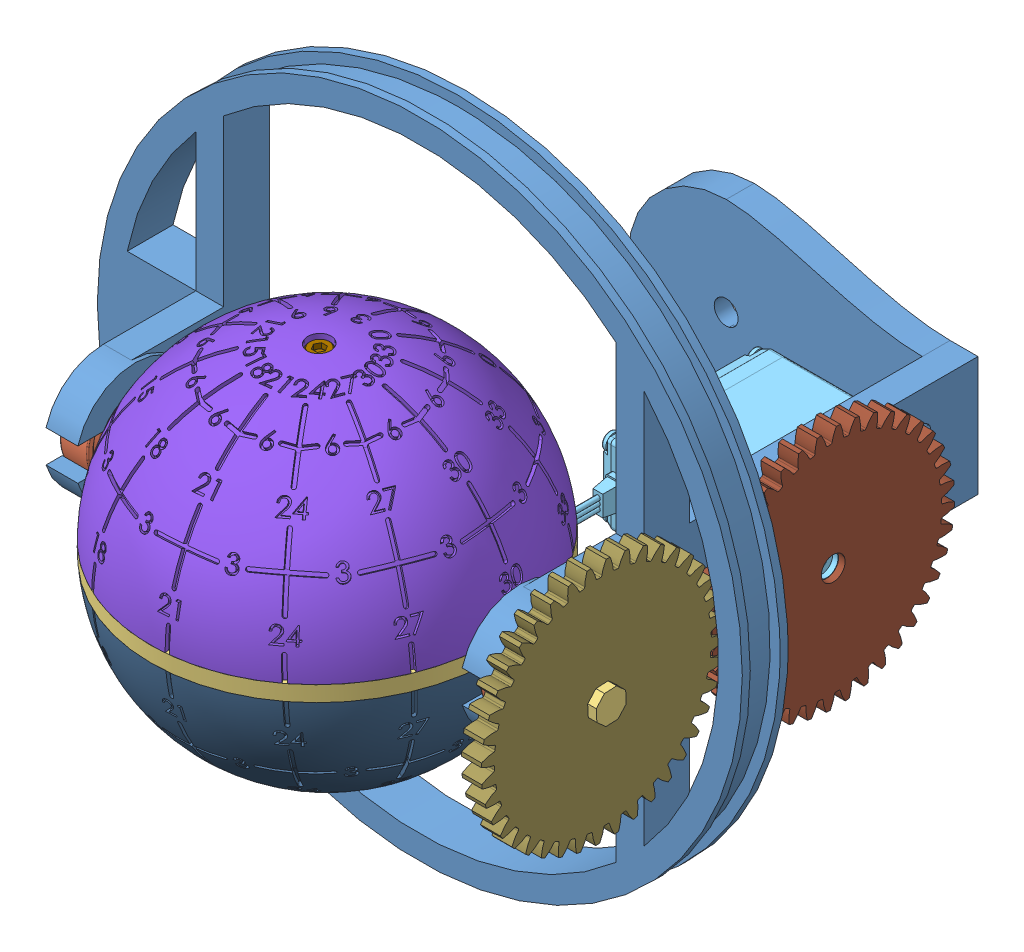
SolidWorks assembly Pitch2, configuration Default. Lengths in mm.
Overall size (162 162 168.07).
16 component instances, 12 part files, 15 mates.
Components (placement in the parent):
- PitchBracketV2-1: PitchBracketV2 [Default] at origin size (162 162 121.57)
- Ball Bearing 608ZZ-2: Ball Bearing 608ZZ [Défaut] at (-52.75 0 -1.875) x (0 0 -1) z (-1 0 0) size (22 22 7)
- Ball Bearing 608ZZ-3: Ball Bearing 608ZZ [Défaut] at (52.75 0 -1.875) x (0 0 -1) z (1 0 0) size (22 22 7)
- Yaw-1: Yaw [Default] at (-53.019 -60.801 -96.8449) x (1 0 0) z (0 -0.046911 0.998899) size (130.2 88.9 117.86)
  - BallPlate-1: BallPlate [Default] at (53.019 65.1893 92.0131) size (127.54 8 88.9)
  - SKF 625-1: SKF 625 [Default] at (53.019 62.6893 92.0131) x (0 1 0) z (-0.440998 0 0.897508) size (5 16 16)
  - Servo-1: Servo [noHorn] at (53.019 67.1893 71.9881) x (0 0 -1) z (1 0 0) size (19.8 47.23 67)
  - YawServoGear-1: YawServoGear [Default] at (42.719 84.6893 71.9881) x (-0.590306 0 0.80718) z (0 -1 0) size (24.43 24.43 4)
  - BallShaft_V2-1: BallShaft_V2 [Default] at (53.019 65.1893 92.0131) x (-0.986105 0 0.166123) z (-0.166123 0 -0.986105) size (24.43 75.9 24.43)
  - Ball_V9.1_Top-1: Ball_V9.1_Top [Default] at (53.019 65.1893 92.0131) x (-0.907868 0 -0.419257) z (0.419257 0 -0.907868) size (88.8 42.45 88.81)
  - socket head cap screw_am-1: socket head cap screw_am [B18.3.1M - 3 x 0.5 x 20 Hex SHCS -- 20SHX] at (53.019 108.6393 92.0131) x (0 -1 0) z (0 0 1) size (23 5.5 5.5)
  - Ball_V9.1_Bot-1: Ball_V9.1_Bot [Default] at (53.019 65.1893 92.0131) x (-0.907868 0 -0.419257) z (0.419257 0 -0.907868) size (88.8 87.56 88.81)
  - socket head cap screw_am-2: socket head cap screw_am [B18.3.1M - 3 x 0.5 x 20 Hex SHCS -- 20SHX] at (53.019 21.7393 92.0131) x (0 1 0) z (0.546944 0 -0.837169) size (23 5.5 5.5)
- Servo-1: Servo [Default] at (47.25 0 -70.05) x (0 1 0) z (0 0 -1) size (19.8 47.23 67)
- PitchServoGear-1: PitchServoGear [Default] at (69.15 0 -59.75) x (0 -0.80252 -0.596625) z (-1 0 0) size (60.99 60.99 5)
- PitchGear-1: PitchGear [Default] at (64.15 0 -1.875) x (0 0.061118 -0.998131) z (1 0 0) size (60.99 60.99 12.6)
Mates (geometry in assembly coordinates):
- Concentric2: concentric: circle of PitchBracketV2-1; circle of Ball Bearing 608ZZ-2
- Width2: width: plane of PitchBracketV2-1 through (-56.25 -15 -55.6183) normal (-1 0 0); plane of PitchBracketV2-1 through (-49.25 0 -152.5832) normal (1 0 0); plane of Ball Bearing 608ZZ-2 through (-49.25 0 -1.875) normal (1 0 0); plane of Ball Bearing 608ZZ-2 through (-56.25 0 -1.875) normal (-1 0 0)
- Concentric3: concentric: circle of Ball Bearing 608ZZ-3; circle of PitchBracketV2-1
- Width3: width: plane of PitchBracketV2-1 through (49.25 15 0) normal (-1 0 0); plane of PitchBracketV2-1 through (56.25 15 0) normal (1 0 0); plane of Ball Bearing 608ZZ-3 through (56.25 0 -1.875) normal (1 0 0); plane of Ball Bearing 608ZZ-3 through (49.25 0 -1.875) normal (-1 0 0)
- Concentric4: concentric: circle of PitchBracketV2-1; circle of Yaw-1/BallPlate-1
- Width4: width: plane of PitchBracketV2-1 through (-56.25 -15 -55.6183) normal (-1 0 0); plane of PitchBracketV2-1 through (56.25 15 0) normal (1 0 0); plane of Yaw-1/BallPlate-1 through (46.45 1.9978 -1.7812) normal (1 0 0); plane of Yaw-1/BallPlate-1 through (-46.45 1.9978 -1.7812) normal (-1 0 0)
- Width5: width: plane of PitchBracketV2-1 through (0 -15 0) normal (0 -1 0); plane of PitchBracketV2-1 through (0 15 0) normal (0 1 0); plane of Servo-1 through (47.25 9.9 -49.75) normal (0 1 0); plane of Servo-1 through (47.25 -9.9 -49.75) normal (0 -1 0)
- Concentric5: concentric: circle of Servo-1; circle of PitchServoGear-1
- Coincident1: coincident: plane of Servo-1 through (67.15 0 -59.75) normal (1 0 0); plane of PitchServoGear-1 through (67.15 0 -59.75) normal (-1 0 0)
- Coincident3: coincident: plane of PitchBracketV2-1 through (56.25 15 0) normal (1 0 0); plane of Servo-1 through (56.25 0 -70.05) normal (1 0 0)
- Concentric8: concentric: circle of PitchBracketV2-1; circle of PitchGear-1
- Coincident5: coincident: plane of PitchServoGear-1 through (69.15 0 -59.75) normal (1 0 0); plane of PitchGear-1 through (69.15 0 -1.875) normal (1 0 0)
- GearMate1: gear = 1 : 1 mm: cylinder of PitchGear-1 through (38.8723 0 -1.875) axis (1 0 0) radius 6.25; cylinder of Yaw-1/BallPlate-1 through (-76.4354 0 -1.875) axis (-1 0 0) radius 4
- GearMate2: gear = 12.5 : 12.5 mm: circle of PitchServoGear-1; cylinder of PitchGear-1 through (38.8723 0 -1.875) axis (1 0 0) radius 6.25
- Lock1: lock: unknown of PitchBracketV2-1; unknown of Servo-1
